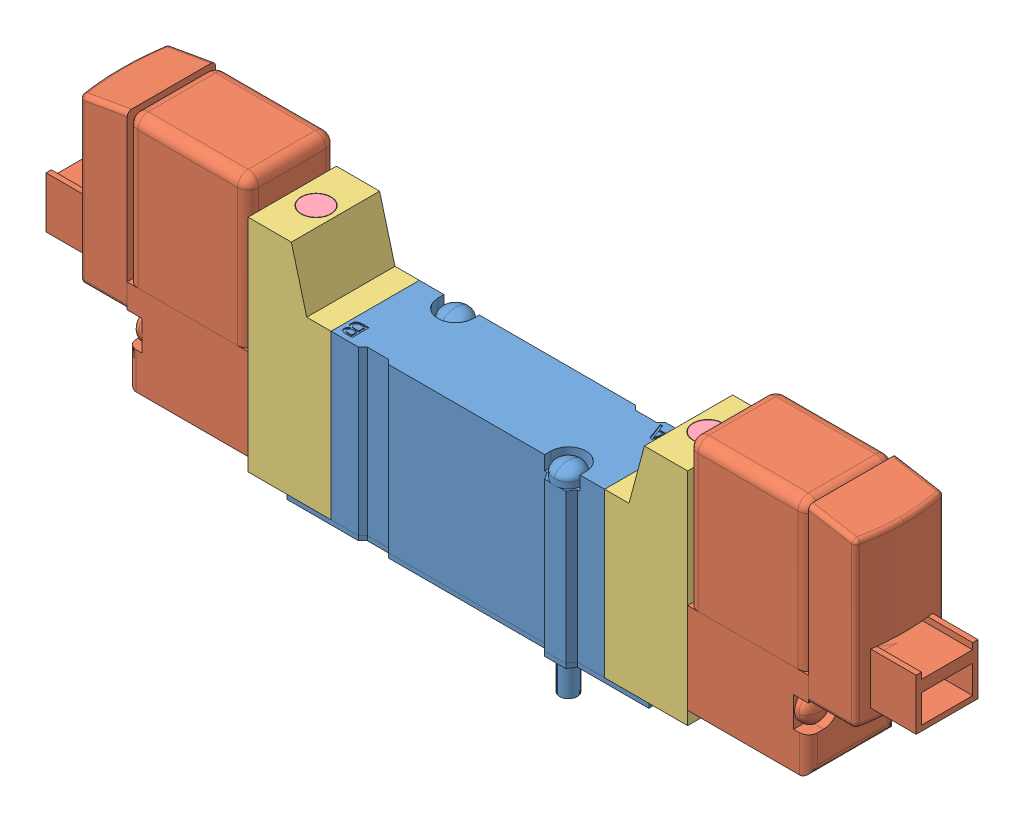
SolidWorks assembly Double Solenoid Valve 217-2948, configuration Default. Lengths in mm.
Overall size (98.6 32.6 11.8).
7 component instances, 4 part files, 0 mates.
Components (placement in the parent):
- Copy of 217-2948-001 Rev1_40^Double Solenoid Valve 217-2948-1: Copy of 217-2948-001 Rev1_40^Double Solenoid Valve 217-2948 [Default] at origin size (41 22.7 11.8) (virtual)
- Copy of 217-2948-002 Rev1_L-1^Double Solenoid Valve 217-2948-1: Copy of 217-2948-002 Rev1_L-1^Double Solenoid Valve 217-2948 [Default] at (24.9 1.5 0) x (0 -1 0) z (0 0 1) size (27 28.2 10) (virtual)
- Copy of 217-2948-002 Rev1_L-1^Double Solenoid Valve 217-2948-2: Copy of 217-2948-002 Rev1_L-1^Double Solenoid Valve 217-2948 [Default] at (-24.9 1.5 0) x (0 -1 0) z (0 0 -1) size (27 28.2 10) (virtual)
- Copy of 217-2948-003 Rev1_SingleA^Double Solenoid Valve 217-2948-1: Copy of 217-2948-003 Rev1_SingleA^Double Solenoid Valve 217-2948 [Default] at (-15.5 0 0) size (9.4 25 10) (virtual)
- Copy of 217-2948-003 Rev1_SingleA^Double Solenoid Valve 217-2948-2: Copy of 217-2948-003 Rev1_SingleA^Double Solenoid Valve 217-2948 [Default] at (15.5 0 0) x (-1 0 0) z (0 0 -1) size (9.4 25 10) (virtual)
- Copy of 217-2948-005 Rev1_P^Double Solenoid Valve 217-2948-1: Copy of 217-2948-005 Rev1_P^Double Solenoid Valve 217-2948 [Default] at (22.2 24.5 0) x (-0.965926 0 -0.258819) z (0.258819 0 -0.965926) size (3.3 0.5 3.3) (virtual)
- Copy of 217-2948-005 Rev1_P^Double Solenoid Valve 217-2948-2: Copy of 217-2948-005 Rev1_P^Double Solenoid Valve 217-2948 [Default] at (-22.2 24.5 0) x (-0.965926 0 0.258819) z (-0.258819 0 -0.965926) size (3.3 0.5 3.3) (virtual)
